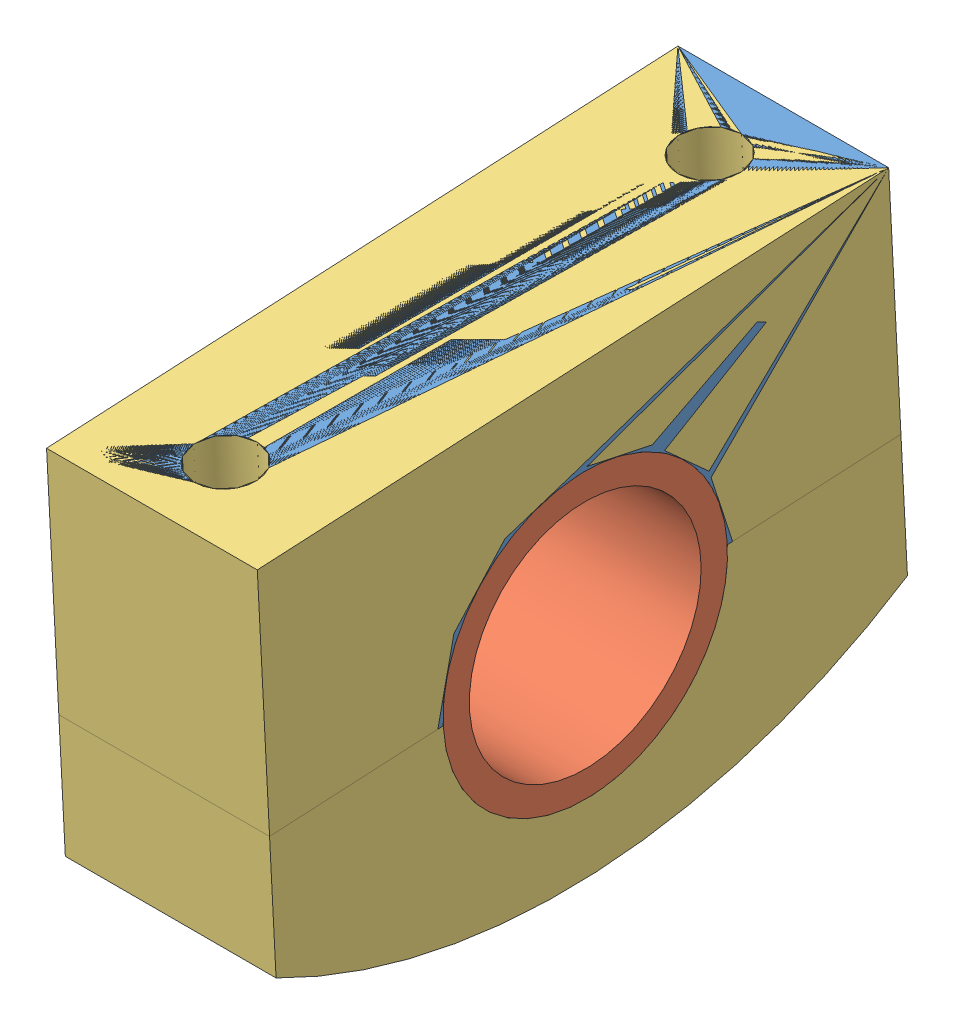
SolidWorks assembly rearsupportassem, configuration 預設. Lengths in mm.
Overall size (20 44.09 62.27).
3 component instances, 3 part files, 15 mates.
Components (placement in the parent):
- A7320_Rear_Lower_Mount-1: A7320_Rear_Lower_Mount [預設] at (-12.8358 -204.6747 61.0563) size (20 25.59 61.08)
- A7320_Rear_ARB_Bar_Spacer-1: A7320_Rear_ARB_Bar_Spacer [預設] at (-12.8358 -25.36 4049.6092) x (0 -0.924225 -0.381849) z (1 0 0) size (27 27 20)
- A7320_Rear_Upper_Mount-1: A7320_Rear_Upper_Mount [預設] at (-12.8358 -204.6747 61.0563) size (20 21.6 61.11)
Mates (geometry in assembly coordinates):
- 同軸心1: concentric aligned: cylinder of lower support base ver4-1 through (-2.8358 -32.6459 4026.2016) axis (0 0.998665 0.051655) radius 3; cylinder of upper support base ver4-1 through (-2.8358 -44.1452 4025.6068) axis (0 0.998665 0.051655) radius 3
- 同軸心2: concentric aligned: cylinder of lower support base ver4-1 through (-2.8358 -35.022 4072.1402) axis (0 0.998665 0.051655) radius 3; cylinder of upper support base ver4-1 through (-2.8358 -46.5213 4071.5454) axis (0 0.998665 0.051655) radius 3
- 同軸心3: concentric anti-aligned: cylinder of A7320_Rear_Lower_Mount-1 through (7.1642 -25.36 4049.6092) axis (-1 0 0) radius 13.5; cylinder of 定位片-1 through (-16.8358 -25.36 4049.6092) axis (1 0 0) radius 12.5
- 重合/共線/共點2: coincident anti-aligned: plane of A7320_Rear_Lower_Mount-1 through (-12.8358 -204.6747 61.0563) normal (-1 0 0); plane of 定位片-1 through (-12.8358 -25.36 4049.6092) normal (1 0 0)
- 同軸心4: concentric aligned: cylinder of lower support base ver4-1 through (7.1642 -25.36 4049.6092) axis (-1 0 0) radius 13.5; cylinder of Rear_Spacer-1 through (7.1642 -25.36 4049.6092) axis (-1 0 0) radius 13.5
- 重合/共線/共點3: coincident anti-aligned: plane of A7320_Rear_ARB_Bar_Spacer-1 through (-12.8358 -25.36 4049.6092) normal (-1 0 0); plane of 定位片-1 through (-12.8358 -25.36 4049.6092) normal (1 0 0)
- 同軸心5: concentric anti-aligned: cylinder of lower support base ver4-1 through (-20.8358 -11.2409 4028.3101) axis (0 0.998665 0.051655) radius 2.5; cylinder of heavy hex flange screw_am-1 through (-20.8358 -12.0399 4028.2688) axis (0 -0.998665 -0.051655) radius 2.5
- 重合/共線/共點4: coincident anti-aligned: plane of lower support base ver4-1 through (-28.8358 -6.6608 4036.5577) normal (0 -0.998665 -0.051655); plane of heavy hex flange screw_am-1 through (-25.4485 -6.2353 4028.3301) normal (0 0.998665 0.051655)
- 同軸心6: concentric anti-aligned: cylinder of lower support base ver4-1 through (-20.8358 -13.5137 4072.2514) axis (0 0.998665 0.051655) radius 2.5; cylinder of heavy hex flange screw_am-2 through (-20.8358 -14.3127 4072.21) axis (0 -0.998665 -0.051655) radius 2.5
- 重合/共線/共點5: coincident anti-aligned: plane of lower support base ver4-1 through (-28.8358 -8.1072 4064.5203) normal (0 -0.998665 -0.051655); plane of heavy hex flange screw_am-2 through (-25.4485 -8.5081 4072.2714) normal (0 0.998665 0.051655)
- 同軸心8: concentric anti-aligned: cylinder of lower support base ver4-1 through (15.1642 -11.2409 4028.3101) axis (0 0.998665 0.051655) radius 2.5; cylinder of heavy hex flange screw_am-4 through (15.1642 -12.0399 4028.2688) axis (0 -0.998665 -0.051655) radius 2.5
- 重合/共線/共點6: coincident anti-aligned: plane of lower support base ver4-1 through (7.1642 -6.6608 4036.5577) normal (0 -0.998665 -0.051655); plane of heavy hex flange screw_am-4 through (10.5515 -6.2353 4028.3301) normal (0 0.998665 0.051655)
- 同軸心9: concentric anti-aligned: cylinder of lower support base ver4-1 through (15.1642 -13.5137 4072.2514) axis (0 0.998665 0.051655) radius 2.5; cylinder of heavy hex flange screw_am-5 through (15.1642 -14.3127 4072.21) axis (0 -0.998665 -0.051655) radius 2.5
- 重合/共線/共點7: coincident anti-aligned: plane of lower support base ver4-1 through (7.1642 -8.1072 4064.5203) normal (0 -0.998665 -0.051655); plane of heavy hex flange screw_am-5 through (10.5515 -8.5081 4072.2714) normal (0 0.998665 0.051655)
- 重合/共線/共點8: coincident anti-aligned: plane of lower support base ver4-1 through (7.1642 -23.8103 4019.6493) normal (0 -0.998665 -0.051655); plane of upper support base ver4-1 through (7.1642 -26.9096 4079.5692) normal (0 0.998665 0.051655)
